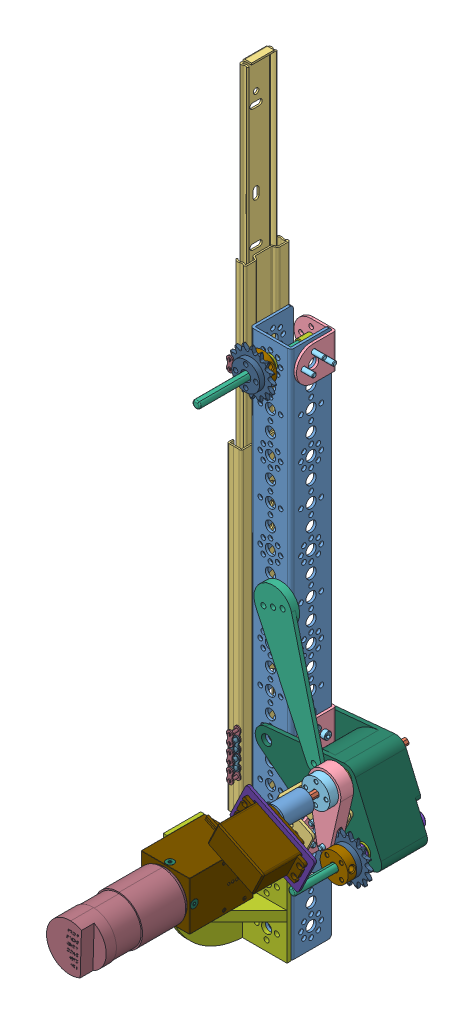
SolidWorks assembly 8699-18-204 Lander Latcher Drive, configuration Open. Lengths in mm.
Overall size (146.92 588.89 235.96).
103 component instances, 43 part files, 109 mates.
Components (placement in the parent):
- tetrix_739069-2: tetrix_739069 [Default] at (0 192 32) x (1 0 0) z (0 1 0) size (32 32 416)
- am-3643 NeveRest Sport, 104-1 with Motor-1: am-3643 NeveRest Sport, 104-1 with Motor [Default] at (37.7484 -95.467 21.4494) x (0 -1 0) z (0 0 1) size (48.85 48.85 145.31)
  - am-3643 NeveRest Sport, 104-1 with Motor(2)^am-3643 NeveRest Sport, 104-1 with Motor-1: am-3643 NeveRest Sport, 104-1 with Motor(2)^am-3643 NeveRest Sport, 104-1 with Motor [Default] at origin size (48.85 48.85 145.31) (virtual)
    - dv-XXXX Output Plug - 550 Sport^am-3643 NeveRest Sport, 104-1 with Motor(2)_am-3643 NeveRest Sport, 104-1 with Motor-1: dv-XXXX Output Plug - 550 Sport^am-3643 NeveRest Sport, 104-1 with Motor(2)_am-3643 NeveRest Sport, 104-1 with Motor [Default] at (30.7788 -45.9281 37.6212) x (-0.707107 -0.707107 0) z (0 0 1) size (34.54 34.54 34.87) (virtual)
      - dv-XXXX Output Plug with orbital bolt circle^dv-XXXX Output Plug - 550 Sport_am-3643 NeveRest Sport, 104-1 with Motor(2)_am-3643 NeveRest Sport, 104-1 with Motor-1: dv-XXXX Output Plug with orbital bolt circle^dv-XXXX Output Plug - 550 Sport_am-3643 NeveRest Sport, 104-1 with Motor(2)_am-3643 NeveRest Sport, 104-1 with Motor [Default] at (-7.0244 -4.5434 5.3964) size (34.54 34.54 17.78) (virtual)
      - BALL BEARING_5972K154^dv-XXXX Output Plug - 550 Sport_am-3643 NeveRest Sport, 104-1 with Motor(2)_am-3643 NeveRest Sport, 104-1 with Motor-1: BALL BEARING_5972K154^dv-XXXX Output Plug - 550 Sport_am-3643 NeveRest Sport, 104-1 with Motor(2)_am-3643 NeveRest Sport, 104-1 with Motor [Default] at (-7.0244 -4.5434 -0.8666) size (21 21 5) (virtual)
      - BALL BEARING_5972K154^dv-XXXX Output Plug - 550 Sport_am-3643 NeveRest Sport, 104-1 with Motor(2)_am-3643 NeveRest Sport, 104-1 with Motor-2: BALL BEARING_5972K154^dv-XXXX Output Plug - 550 Sport_am-3643 NeveRest Sport, 104-1 with Motor(2)_am-3643 NeveRest Sport, 104-1 with Motor [Default] at (-7.0244 -4.5434 10.1354) size (21 21 5) (virtual)
      - Nub Shaft^dv-XXXX Output Plug - 550 Sport_am-3643 NeveRest Sport, 104-1 with Motor(2)_am-3643 NeveRest Sport, 104-1 with Motor-1: Nub Shaft^dv-XXXX Output Plug - 550 Sport_am-3643 NeveRest Sport, 104-1 with Motor(2)_am-3643 NeveRest Sport, 104-1 with Motor [Default] at (-7.0244 -4.5434 20.2536) x (-0.939267 -0.343187 0) z (0.343187 -0.939267 0) size (19.05 34.87 19.05) (virtual)
    - dv-XXXX Carrier Stage 4-1 Planet, 5-1 Sun - 550 Sport^am-3643 NeveRest Sport, 104-1 with Motor(2)_am-3643 NeveRest Sport, 104-1 with Motor-1: dv-XXXX Carrier Stage 4-1 Planet, 5-1 Sun - 550 Sport^am-3643 NeveRest Sport, 104-1 with Motor(2)_am-3643 NeveRest Sport, 104-1 with Motor [Default] at (63.7059 -27.5277 100.4568) x (0.941837 -0.336071 0) z (-0.336071 -0.941837 0) size (29.23 15.47 28.59) (virtual)
      - am-2892+15T+pinion+3.2mm+bore^dv-XXXX Carrier Stage 4-1 Planet, 5-1 Sun - 550 Sport_am-3643 NeveRest Sport, 104-1 with Motor(2)_am-3643 NeveRest Sport, 104-1 with Motor-1: am-2892+15T+pinion+3.2mm+bore^dv-XXXX Carrier Stage 4-1 Planet, 5-1 Sun - 550 Sport_am-3643 NeveRest Sport, 104-1 with Motor(2)_am-3643 NeveRest Sport, 104-1 with Motor [Default] at (-25.9249 -17.3194 11.1026) x (0 -1 0) z (0.056322 0 -0.998413) size (5.31 10.12 10.18) (virtual)
      - am-2892+15T+pinion+3.2mm+bore^dv-XXXX Carrier Stage 4-1 Planet, 5-1 Sun - 550 Sport_am-3643 NeveRest Sport, 104-1 with Motor(2)_am-3643 NeveRest Sport, 104-1 with Motor-2: am-2892+15T+pinion+3.2mm+bore^dv-XXXX Carrier Stage 4-1 Planet, 5-1 Sun - 550 Sport_am-3643 NeveRest Sport, 104-1 with Motor(2)_am-3643 NeveRest Sport, 104-1 with Motor [Default] at (-16.9249 -17.3194 20.1026) x (0 -1 0) z (-0.169038 0 -0.98561) size (5.31 10.12 10.18) (virtual)
      - am-2892+15T+pinion+3.2mm+bore^dv-XXXX Carrier Stage 4-1 Planet, 5-1 Sun - 550 Sport_am-3643 NeveRest Sport, 104-1 with Motor(2)_am-3643 NeveRest Sport, 104-1 with Motor-3: am-2892+15T+pinion+3.2mm+bore^dv-XXXX Carrier Stage 4-1 Planet, 5-1 Sun - 550 Sport_am-3643 NeveRest Sport, 104-1 with Motor(2)_am-3643 NeveRest Sport, 104-1 with Motor [Default] at (-25.9249 -17.3194 29.1026) x (0 -1 0) z (-0.027474 0 -0.999623) size (5.31 10.12 10.18) (virtual)
      - am-2892+15T+pinion+3.2mm+bore^dv-XXXX Carrier Stage 4-1 Planet, 5-1 Sun - 550 Sport_am-3643 NeveRest Sport, 104-1 with Motor(2)_am-3643 NeveRest Sport, 104-1 with Motor-4: am-2892+15T+pinion+3.2mm+bore^dv-XXXX Carrier Stage 4-1 Planet, 5-1 Sun - 550 Sport_am-3643 NeveRest Sport, 104-1 with Motor(2)_am-3643 NeveRest Sport, 104-1 with Motor [Default] at (-34.9249 -17.3194 20.1026) x (0 -1 0) z (-0.064746 0 -0.997902) size (5.31 10.12 10.18) (virtual)
      - dv-XXXX - Carrier Plate 4-1 Planet, 5-1 Sun^dv-XXXX Carrier Stage 4-1 Planet, 5-1 Sun - 550 Sport_am-3643 NeveRest Sport, 104-1 with Motor(2)_am-3643 NeveRest Sport, 104-1 with Motor-1: dv-XXXX - Carrier Plate 4-1 Planet, 5-1 Sun^dv-XXXX Carrier Stage 4-1 Planet, 5-1 Sun - 550 Sport_am-3643 NeveRest Sport, 104-1 with Motor(2)_am-3643 NeveRest Sport, 104-1 with Motor [Default] at (-25.9249 -27.154 20.1026) size (25.04 10 25.04) (virtual)
      - 11T+pinion+3.2mm+bore^dv-XXXX Carrier Stage 4-1 Planet, 5-1 Sun - 550 Sport_am-3643 NeveRest Sport, 104-1 with Motor(2)_am-3643 NeveRest Sport, 104-1 with Motor-1: 11T+pinion+3.2mm+bore^dv-XXXX Carrier Stage 4-1 Planet, 5-1 Sun - 550 Sport_am-3643 NeveRest Sport, 104-1 with Motor(2)_am-3643 NeveRest Sport, 104-1 with Motor [Default] at (-25.9249 -22.6277 20.1026) x (0 -1 0) z (-0.988725 0 -0.149745) size (10 7.67 7.74) (virtual)
    - dv-XXXX Carrier Stage 5-1 Planet, 5-1 Sun^am-3643 NeveRest Sport, 104-1 with Motor(2)_am-3643 NeveRest Sport, 104-1 with Motor-1: dv-XXXX Carrier Stage 5-1 Planet, 5-1 Sun^am-3643 NeveRest Sport, 104-1 with Motor(2)_am-3643 NeveRest Sport, 104-1 with Motor [Default] at (6.8131 -34.6705 55.7021) x (-0.996841 0.079427 0) z (0.079427 0.996841 0) size (29.78 15.47 28.75) (virtual)
      - dv-XXXX - Carrier Plate 5-1 Planet, 5-1 Sun^dv-XXXX Carrier Stage 5-1 Planet, 5-1 Sun_am-3643 NeveRest Sport, 104-1 with Motor(2)_am-3643 NeveRest Sport, 104-1 with Motor-1: dv-XXXX - Carrier Plate 5-1 Planet, 5-1 Sun^dv-XXXX Carrier Stage 5-1 Planet, 5-1 Sun_am-3643 NeveRest Sport, 104-1 with Motor(2)_am-3643 NeveRest Sport, 104-1 with Motor [Default] at (-26.6144 7.6007 0.9439) size (25.04 10 25.04) (virtual)
      - 17T+pinion+3.2mm+bore^dv-XXXX Carrier Stage 5-1 Planet, 5-1 Sun_am-3643 NeveRest Sport, 104-1 with Motor(2)_am-3643 NeveRest Sport, 104-1 with Motor-1: 17T+pinion+3.2mm+bore^dv-XXXX Carrier Stage 5-1 Planet, 5-1 Sun_am-3643 NeveRest Sport, 104-1 with Motor(2)_am-3643 NeveRest Sport, 104-1 with Motor [Default] at (-35.0144 12.127 0.9439) x (0 1 0) z (-0.112997 0 0.993595) size (5.31 11.33 11.37) (virtual)
      - 17T+pinion+3.2mm+bore^dv-XXXX Carrier Stage 5-1 Planet, 5-1 Sun_am-3643 NeveRest Sport, 104-1 with Motor(2)_am-3643 NeveRest Sport, 104-1 with Motor-2: 17T+pinion+3.2mm+bore^dv-XXXX Carrier Stage 5-1 Planet, 5-1 Sun_am-3643 NeveRest Sport, 104-1 with Motor(2)_am-3643 NeveRest Sport, 104-1 with Motor [Default] at (-26.6144 12.127 9.3439) x (0 1 0) z (0.065842 0 0.99783) size (5.31 11.33 11.37) (virtual)
      - 17T+pinion+3.2mm+bore^dv-XXXX Carrier Stage 5-1 Planet, 5-1 Sun_am-3643 NeveRest Sport, 104-1 with Motor(2)_am-3643 NeveRest Sport, 104-1 with Motor-3: 17T+pinion+3.2mm+bore^dv-XXXX Carrier Stage 5-1 Planet, 5-1 Sun_am-3643 NeveRest Sport, 104-1 with Motor(2)_am-3643 NeveRest Sport, 104-1 with Motor [Default] at (-26.6144 12.127 -7.4561) x (0 1 0) z (0.038378 0 0.999263) size (5.31 11.33 11.37) (virtual)
      - 17T+pinion+3.2mm+bore^dv-XXXX Carrier Stage 5-1 Planet, 5-1 Sun_am-3643 NeveRest Sport, 104-1 with Motor(2)_am-3643 NeveRest Sport, 104-1 with Motor-4: 17T+pinion+3.2mm+bore^dv-XXXX Carrier Stage 5-1 Planet, 5-1 Sun_am-3643 NeveRest Sport, 104-1 with Motor(2)_am-3643 NeveRest Sport, 104-1 with Motor [Default] at (-18.2144 12.127 0.9439) x (0 1 0) z (0.205012 0 0.978759) size (5.31 11.33 11.37) (virtual)
      - 13T+pinion+3.2mm+bore^dv-XXXX Carrier Stage 5-1 Planet, 5-1 Sun_am-3643 NeveRest Sport, 104-1 with Motor(2)_am-3643 NeveRest Sport, 104-1 with Motor-1: 13T+pinion+3.2mm+bore^dv-XXXX Carrier Stage 5-1 Planet, 5-1 Sun_am-3643 NeveRest Sport, 104-1 with Motor(2)_am-3643 NeveRest Sport, 104-1 with Motor [Default] at (-26.6144 12.127 0.9439) x (0 -1 0) z (-0.984718 0 0.174154) size (10 8.9 8.96) (virtual)
    - dv-XXXX Carrier Stage 5-1 Planet, 0.3125 hex output^am-3643 NeveRest Sport, 104-1 with Motor(2)_am-3643 NeveRest Sport, 104-1 with Motor-1: dv-XXXX Carrier Stage 5-1 Planet, 0.3125 hex output^am-3643 NeveRest Sport, 104-1 with Motor(2)_am-3643 NeveRest Sport, 104-1 with Motor [Default] at (38.8348 -52.014 37.7173) x (0.574594 -0.818439 0) z (-0.818439 -0.574594 0) size (30.46 10 28.73) (virtual)
      - dv-XXXX - Carrier Plate 5-1 Planet, 0.3125 hex output^dv-XXXX Carrier Stage 5-1 Planet, 0.3125 hex output_am-3643 NeveRest Sport, 104-1 with Motor(2)_am-3643 NeveRest Sport, 104-1 with Motor-1: dv-XXXX - Carrier Plate 5-1 Planet, 0.3125 hex output^dv-XXXX Carrier Stage 5-1 Planet, 0.3125 hex output_am-3643 NeveRest Sport, 104-1 with Motor(2)_am-3643 NeveRest Sport, 104-1 with Motor [Default] at (-16.3468 15.5854 -4.8585) size (25.04 10 25.04) (virtual)
      - 17T+pinion+3.2mm+bore^dv-XXXX Carrier Stage 5-1 Planet, 0.3125 hex output_am-3643 NeveRest Sport, 104-1 with Motor(2)_am-3643 NeveRest Sport, 104-1 with Motor-1: 17T+pinion+3.2mm+bore^dv-XXXX Carrier Stage 5-1 Planet, 0.3125 hex output_am-3643 NeveRest Sport, 104-1 with Motor(2)_am-3643 NeveRest Sport, 104-1 with Motor [Default] at (-24.7468 20.1117 -4.8585) x (0 1 0) z (0.867721 0 0.497051) size (5.31 11.33 11.37) (virtual)
      - 17T+pinion+3.2mm+bore^dv-XXXX Carrier Stage 5-1 Planet, 0.3125 hex output_am-3643 NeveRest Sport, 104-1 with Motor(2)_am-3643 NeveRest Sport, 104-1 with Motor-2: 17T+pinion+3.2mm+bore^dv-XXXX Carrier Stage 5-1 Planet, 0.3125 hex output_am-3643 NeveRest Sport, 104-1 with Motor(2)_am-3643 NeveRest Sport, 104-1 with Motor [Default] at (-16.3468 20.1117 3.5415) x (0 1 0) z (-0.061129 0 0.99813) size (5.31 11.33 11.37) (virtual)
      - 17T+pinion+3.2mm+bore^dv-XXXX Carrier Stage 5-1 Planet, 0.3125 hex output_am-3643 NeveRest Sport, 104-1 with Motor(2)_am-3643 NeveRest Sport, 104-1 with Motor-3: 17T+pinion+3.2mm+bore^dv-XXXX Carrier Stage 5-1 Planet, 0.3125 hex output_am-3643 NeveRest Sport, 104-1 with Motor(2)_am-3643 NeveRest Sport, 104-1 with Motor [Default] at (-16.3468 20.1117 -13.2585) x (0 1 0) z (0.038378 0 0.999263) size (5.31 11.33 11.37) (virtual)
      - 17T+pinion+3.2mm+bore^dv-XXXX Carrier Stage 5-1 Planet, 0.3125 hex output_am-3643 NeveRest Sport, 104-1 with Motor(2)_am-3643 NeveRest Sport, 104-1 with Motor-4: 17T+pinion+3.2mm+bore^dv-XXXX Carrier Stage 5-1 Planet, 0.3125 hex output_am-3643 NeveRest Sport, 104-1 with Motor(2)_am-3643 NeveRest Sport, 104-1 with Motor [Default] at (-7.9468 20.1117 -4.8585) x (0 1 0) z (0.040503 0 0.999179) size (5.31 11.33 11.37) (virtual)
    - neveRest+15T+pinion^am-3643 NeveRest Sport, 104-1 with Motor(2)_am-3643 NeveRest Sport, 104-1 with Motor-1: neveRest+15T+pinion^am-3643 NeveRest Sport, 104-1 with Motor(2)_am-3643 NeveRest Sport, 104-1 with Motor [Default] at (-29.3619 -57.8483 143.121) x (-0.999543 0.030232 0) z (0 0 -1) size (38 38 89.79) (virtual)
      - am-3104 NeveRest Motor^neveRest+15T+pinion_am-3643 NeveRest Sport, 104-1 with Motor(2)_am-3643 NeveRest Sport, 104-1 with Motor-1: am-3104 NeveRest Motor^neveRest+15T+pinion_am-3643 NeveRest Sport, 104-1 with Motor(2)_am-3643 NeveRest Sport, 104-1 with Motor [Default] at (-61.259 21.9619 50.009) size (38 38 85.19) (virtual)
      - 15T+pinion+3.2mm+bore+motor^neveRest+15T+pinion_am-3643 NeveRest Sport, 104-1 with Motor(2)_am-3643 NeveRest Sport, 104-1 with Motor-1: 15T+pinion+3.2mm+bore+motor^neveRest+15T+pinion_am-3643 NeveRest Sport, 104-1 with Motor(2)_am-3643 NeveRest Sport, 104-1 with Motor [Default] at (-61.259 21.9619 54.7947) x (0 0 1) z (-0.930076 -0.367368 0) size (9.81 10.12 10.18) (virtual)
    - 91294A126_BLACK ALLOY STEEL FLAT-HEAD SOCKET CAP SCREW_91294A126^am-3643 NeveRest Sport, 104-1 with Motor(2)_am-3643 NeveRest Sport, 104-1 with Motor-1: 91294A126_BLACK ALLOY STEEL FLAT-HEAD SOCKET CAP SCREW_91294A126^am-3643 NeveRest Sport, 104-1 with Motor(2)_am-3643 NeveRest Sport, 104-1 with Motor [Default] at (13.433 -37.7484 46.9556) x (0 0 1) z (-1 0 0) size (6 6 6.01) (virtual)
    - Thrust Washer^am-3643 NeveRest Sport, 104-1 with Motor(2)_am-3643 NeveRest Sport, 104-1 with Motor-1: Thrust Washer^am-3643 NeveRest Sport, 104-1 with Motor(2)_am-3643 NeveRest Sport, 104-1 with Motor [Default] at (32.533 -37.7484 84.9184) x (0.422278 0.906466 0) z (0 0 -1) size (28.45 28.45 0.51) (virtual)
    - dv-XXXX Motor Mount Plug^am-3643 NeveRest Sport, 104-1 with Motor(2)_am-3643 NeveRest Sport, 104-1 with Motor-1: dv-XXXX Motor Mount Plug^am-3643 NeveRest Sport, 104-1 with Motor(2)_am-3643 NeveRest Sport, 104-1 with Motor [Default] at (32.533 -37.7484 93.1201) x (-0.707107 0.707107 0) z (0 0 -1) size (30.99 30.99 8.13) (virtual)
    - 91294A126_BLACK ALLOY STEEL FLAT-HEAD SOCKET CAP SCREW_91294A126^am-3643 NeveRest Sport, 104-1 with Motor(2)_am-3643 NeveRest Sport, 104-1 with Motor-2: 91294A126_BLACK ALLOY STEEL FLAT-HEAD SOCKET CAP SCREW_91294A126^am-3643 NeveRest Sport, 104-1 with Motor(2)_am-3643 NeveRest Sport, 104-1 with Motor [Default] at (32.533 -18.6484 89.5006) x (0.466078 0 0.884744) z (0 1 0) size (6 6 6.01) (virtual)
    - 91294A126_BLACK ALLOY STEEL FLAT-HEAD SOCKET CAP SCREW_91294A126^am-3643 NeveRest Sport, 104-1 with Motor(2)_am-3643 NeveRest Sport, 104-1 with Motor-3: 91294A126_BLACK ALLOY STEEL FLAT-HEAD SOCKET CAP SCREW_91294A126^am-3643 NeveRest Sport, 104-1 with Motor(2)_am-3643 NeveRest Sport, 104-1 with Motor [Default] at (32.533 -18.6484 46.9556) x (0.982767 0 0.184847) z (0 1 0) size (6 6 6.01) (virtual)
    - 91294A126_BLACK ALLOY STEEL FLAT-HEAD SOCKET CAP SCREW_91294A126^am-3643 NeveRest Sport, 104-1 with Motor(2)_am-3643 NeveRest Sport, 104-1 with Motor-4: 91294A126_BLACK ALLOY STEEL FLAT-HEAD SOCKET CAP SCREW_91294A126^am-3643 NeveRest Sport, 104-1 with Motor(2)_am-3643 NeveRest Sport, 104-1 with Motor [Default] at (13.433 -37.7484 89.5006) x (0 0 1) z (-1 0 0) size (6 6 6.01) (virtual)
    - 91294A126_BLACK ALLOY STEEL FLAT-HEAD SOCKET CAP SCREW_91294A126^am-3643 NeveRest Sport, 104-1 with Motor(2)_am-3643 NeveRest Sport, 104-1 with Motor-5: 91294A126_BLACK ALLOY STEEL FLAT-HEAD SOCKET CAP SCREW_91294A126^am-3643 NeveRest Sport, 104-1 with Motor(2)_am-3643 NeveRest Sport, 104-1 with Motor [Default] at (51.633 -37.7484 46.9556) x (0 -0.421523 0.906818) z (1 0 0) size (6 6 6.01) (virtual)
    - 91294A126_BLACK ALLOY STEEL FLAT-HEAD SOCKET CAP SCREW_91294A126^am-3643 NeveRest Sport, 104-1 with Motor(2)_am-3643 NeveRest Sport, 104-1 with Motor-6: 91294A126_BLACK ALLOY STEEL FLAT-HEAD SOCKET CAP SCREW_91294A126^am-3643 NeveRest Sport, 104-1 with Motor(2)_am-3643 NeveRest Sport, 104-1 with Motor [Default] at (51.633 -37.7484 89.5006) x (0 -0.712248 -0.701928) z (1 0 0) size (6 6 6.01) (virtual)
    - dv-XXXX - 3 Stage 550 Sport Ring Gear Housing^am-3643 NeveRest Sport, 104-1 with Motor(2)_am-3643 NeveRest Sport, 104-1 with Motor-1: dv-XXXX - 3 Stage 550 Sport Ring Gear Housing^am-3643 NeveRest Sport, 104-1 with Motor(2)_am-3643 NeveRest Sport, 104-1 with Motor [Default] at (13.483 -56.7984 68.2281) size (38.1 38.1 49.91) (virtual)
    - 10-32 x 0.25 Set Screw Cup Point^am-3643 NeveRest Sport, 104-1 with Motor(2)_am-3643 NeveRest Sport, 104-1 with Motor-1: 10-32 x 0.25 Set Screw Cup Point^am-3643 NeveRest Sport, 104-1 with Motor(2)_am-3643 NeveRest Sport, 104-1 with Motor [Default] at (42.0774 -42.1846 29.5006) x (-0.906832 0.421492 0) z (0.0498 0.107144 0.992995) size (6.35 4.83 4.83) (virtual)
    - M3x0.5x6mm SHCS_91290A111^am-3643 NeveRest Sport, 104-1 with Motor(2)_am-3643 NeveRest Sport, 104-1 with Motor-1: M3x0.5x6mm SHCS_91290A111^am-3643 NeveRest Sport, 104-1 with Motor(2)_am-3643 NeveRest Sport, 104-1 with Motor [Default] at (23.6942 -46.5873 96.1483) size (5.5 5.5 9.01) (virtual)
    - M3x0.5x6mm SHCS_91290A111^am-3643 NeveRest Sport, 104-1 with Motor(2)_am-3643 NeveRest Sport, 104-1 with Motor-2: M3x0.5x6mm SHCS_91290A111^am-3643 NeveRest Sport, 104-1 with Motor(2)_am-3643 NeveRest Sport, 104-1 with Motor [Default] at (41.3718 -28.9096 96.1483) size (5.5 5.5 9.01) (virtual)
- 11435A110_SIDE-MOUNT DRAWER SLIDE-1: 11435A110_SIDE-MOUNT DRAWER SLIDE [Open] at (-21.6388 1.918 16) x (0 -1 0) z (-1 0 0) size (503.94 45.64 12.7)
- Pitsco Education-739062-1: Pitsco Education-739062 [Default] at (-3.4747 191.2436 18.0384) x (0 -1 0) z (0 0 -1) size (27 31.5 31.5)
- tetrix_739097-1: tetrix_739097 [Default] at (14 192 8) x (0 1 0) z (0 0 1) size (5.74 16.21 5.74)
- tetrix_739097-2: tetrix_739097 [Default] at (14 200 16) x (0 1 0) z (0 0 1) size (5.74 16.21 5.74)
- tetrix_739097-3: tetrix_739097 [Default] at (14 192 24) x (0 1 0) z (0 0 1) size (5.74 16.21 5.74)
- tetrix_744708_6mm-1: tetrix_744708_6mm [Default] at (-41.9477 150.1357 -24.7204) size (6 5.5 100)
- tetrix_739091-7: tetrix_739091 [Default] at (0 192 -3.4) x (1 0 0) z (0 -1 0) size (11 12.4 11)
- tetrix_739091-8: tetrix_739091 [Default] at (0 192 33.4) x (0.999564 -0.029538 0) z (0.029538 0.999564 0) size (11 12.4 11)
- tetrix_739092_collar-2: tetrix_739092_collar [Default] at (0 192 -6.5) size (11 11 6.2)
- tetrix_739079_collar-2: tetrix_739079_collar [Default] at (0 192 44.65) size (22 22 9.5)
- tetrix_739165-3: tetrix_739165 [Default] at (0 192 47.45) size (36 36 6.8)
- tetrix_741665_6mm ID Plastic Bushing_Spacer-1: tetrix_741665_6mm ID Plastic Bushing_Spacer [Default] at (0 192 36.4) x (0.793594 -0.608447 0) z (0 0 1) size (9.4 9.4 3)
- tetrix_741665_6mm ID Plastic Bushing_Spacer-2: tetrix_741665_6mm ID Plastic Bushing_Spacer [Default] at (0 192 34.9) x (-0.923728 -0.383049 0) z (0 0 -1) size (9.4 9.4 3)
- tetrix_744708_6mm-2: tetrix_744708_6mm [Default] at (-41.9477 -169.8643 -61.3204) size (6 5.5 100)
- Pitsco Education-739062-2: Pitsco Education-739062 [Default] at (-3.4747 -128.7564 18.0384) x (0 -1 0) z (0 0 -1) size (27 31.5 31.5)
- tetrix_739091-9: tetrix_739091 [Default] at (0 -128 -3.4) x (-0.332615 -0.943063 0) z (-0.943063 0.332615 0) size (11 12.4 11)
- tetrix_739091-10: tetrix_739091 [Default] at (0 -128 33.4) x (0.998296 -0.058356 0) z (0.058356 0.998296 0) size (11 12.4 11)
- tetrix_739092_collar-3: tetrix_739092_collar [Default] at (0 -128 -6.5) size (11 11 6.2)
- tetrix_739165-4: tetrix_739165 [Default] at (0 -128 44.65) x (-0.343187 0.939267 0) z (0 0 -1) size (36 36 6.8)
- tetrix_739097-4: tetrix_739097 [Default] at (14 -128 24) x (0 1 0) z (0 0 1) size (5.74 16.21 5.74)
- tetrix_739097-5: tetrix_739097 [Default] at (14 -120 16) x (0 1 0) z (0 0 1) size (5.74 16.21 5.74)
- tetrix_739097-6: tetrix_739097 [Default] at (14 -128 8) x (0 1 0) z (0 0 1) size (5.74 16.21 5.74)
- tetrix_739111_BHCS 6-32 x 0.375-1: tetrix_739111_BHCS 6-32 x 0.375 [92949A146] at (-7.5141 -130.7455 38.7958) x (-0.923728 -0.383049 0) z (0 0 -1) size (6.65 6.65 11.49)
- tetrix_739111_BHCS 6-32 x 0.375-2: tetrix_739111_BHCS 6-32 x 0.375 [92949A146] at (7.5141 -125.2545 38.7958) x (-0.923728 -0.383049 0) z (0 0 -1) size (6.65 6.65 11.49)
- tetrix_739097-7: tetrix_739097 [Default] at (-2.7455 -120.4859 40.65) x (0.975434 -0.220292 0) z (0.220292 0.975434 0) size (5.74 16.21 5.74)
- tetrix_39173_outside_link-1: tetrix_39173_outside_link [Default] at (-14.7363 191.7562 46.05) x (0 1 0) z (0 0 1) size (11.43 5.08 7.82)
- tetrix_39173_outside_link-2: tetrix_39173_outside_link [Default] at (-14.7363 -63.2855 46.05) x (0 -1 0) z (0 0 1) size (11.43 5.08 7.82)
- tetrix_39173_outside_link-3: tetrix_39173_outside_link [Default] at (-14.7363 -75.9855 46.05) x (0 -1 0) z (0 0 1) size (11.43 5.08 7.82)
- tetrix_39173_outside_link-4: tetrix_39173_outside_link [Default] at (-14.7363 -88.6855 46.05) x (0 -1 0) z (0 0 1) size (11.43 5.08 7.82)
- tetrix_39173_inside_link-1: tetrix_39173_inside_link [Default] at (-14.7363 -69.6355 46.05) x (0 -1 0) z (0 0 1) size (11.43 5.08 4.9)
- tetrix_39173_inside_link-2: tetrix_39173_inside_link [Default] at (-14.7363 -82.3355 46.05) x (0 -1 0) z (0 0 1) size (11.43 5.08 4.9)
- 8699-18-205 Lander Latcher Drive Adj-1: 8699-18-205 Lander Latcher Drive Adj [Default] at (0 -64 15) x (0.899951 -0.435991 0) z (0 0 1) size (116.51 74.65 143.2)
  - 8699-18-364 Lock Adjustment Plate-1: 8699-18-364 Lock Adjustment Plate [Default] at origin size (108.78 66.42 40)
  - tetrix_739107_32mm_standoff-1: tetrix_739107_32mm_standoff [Default] at (80.8213 0.0145 47.7605) size (7.16 6.2 32)
  - tetrix_741789-1: tetrix_741789 [Default] at (52.7846 32 86) x (1 0 0) z (0 0 -1) size (59.8 60.75 2)
  - tetrix_739197_servo-1: tetrix_739197_servo [Default] at (52.7846 32 88.5) x (0 1 0) z (-1 0 0) size (20 43.2 56.6)
  - tetrix_739278_axle_adapter-1: tetrix_739278_axle_adapter [Default] at (52.7846 32 75.2) x (0.998477 0.055163 0) z (0 0 -1) size (16 16 23)
  - tetrix_739088-1: tetrix_739088 [Default] at (52.7846 32 21.9) x (-0.87123 0.490874 0) z (0 0 -1) size (4.73 4.46 100)
  - tetrix_744708_6mm-2: tetrix_744708_6mm [Default] at (92.5192 -58.7572 -38.7204) x (0.607985 0.793949 0) z (0 0 1) size (6 5.5 100)
  - tetrix_739091-1: tetrix_739091 [Default] at (52.7846 32 -21.4) x (1 0 0) z (0 -1 0) size (11 12.4 11)
  - tetrix_739091-2: tetrix_739091 [Default] at (84.7846 0 21.4) x (-0.82449 0.565877 0) z (-0.565877 -0.82449 0) size (11 12.4 11)
  - tetrix_739091-3: tetrix_739091 [Default] at (84.7846 0 -17.4) x (-0.539749 -0.841826 0) z (-0.841826 0.539749 0) size (11 12.4 11)
  - tetrix_739079_collar-1: tetrix_739079_collar [Default] at (84.7846 0 36.45) x (0.312774 0.949828 0) z (0 0 -1) size (22 22 9.5)
  - tetrix_739165-1: tetrix_739165 [Default] at (84.7846 0 32.45) x (-0.312774 -0.949828 0) z (0 0 1) size (36 36 6.8)
  - tetrix_739065-2: tetrix_739065 [Default] at (36.7846 0 36) x (0 0 1) z (0 1 0) size (32 32 32)
  - tetrix_739091-4: tetrix_739091 [Default] at (52.7846 32 21.4) x (-0.923728 -0.383049 0) z (0.383049 -0.923728 0) size (11 12.4 11)
  - tetrix_739097-1: tetrix_739097 [Default] at (44.7846 0 17) x (0.933008 0.359855 0) z (-0.359855 0.933008 0) size (5.74 16.21 5.74)
  - tetrix_739097-2: tetrix_739097 [Default] at (52.7846 -8 17) x (0.058002 0.998316 0) z (-0.998316 0.058002 0) size (5.74 16.21 5.74)
  - 8699-18-366 Lock-1: 8699-18-366 Lock [Default] at (52.7846 32 31.05) x (0.909547 0.415601 0) z (0 0 1) size (26 57.92 10)
  - tetrix_739097-3: tetrix_739097 [Default] at (69.3764 -4.3113 26.05) x (-0.975108 0.22173 0) z (-0.22173 -0.975108 0) size (5.74 16.21 5.74)
  - tetrix_739172_collar-1: tetrix_739172_collar [Default] at (52.7846 32 36.05) x (-0.909547 -0.415601 0) z (0 0 -1) size (22.1 22.1 9.5)
  - tetrix_739092_collar-1: tetrix_739092_collar [Default] at (84.7846 0 -20.5) x (0.871034 0.491223 0) z (0 0 1) size (11 11 6.2)
  - tetrix_739092_collar-2: tetrix_739092_collar [Default] at (84.7846 0 24.5) x (0.871034 0.491223 0) z (0 0 1) size (11 11 6.2)
- Pitsco Education-739062-3: Pitsco Education-739062 [Default] at (-3.4747 -64.7564 18.0384) x (0 -1 0) z (0 0 -1) size (27 31.5 31.5)
- tetrix_739097-8: tetrix_739097 [Default] at (18 -56 16) x (0 0.381849 -0.924225) z (0 -0.924225 -0.381849) size (5.74 16.21 5.74)
- tetrix_739097-9: tetrix_739097 [Default] at (18 -64 8) x (0 -1 0) z (0 0 1) size (5.74 16.21 5.74)
- tetrix_739097-10: tetrix_739097 [Default] at (18 -64 24) x (0 -1 0) z (0 0 1) size (5.74 16.21 5.74)
- tetrix_739097-13: tetrix_739097 [Default] at (18 -72 16) x (0 1 0) z (0 0 -1) size (5.74 16.21 5.74)
- 8699-18-365 Lock Adjustment Reinforcement-1: 8699-18-365 Lock Adjustment Reinforcement [Default] at (40.062 -58.4877 35) x (0.333979 -0.94258 0) z (-0.94258 -0.333979 0) size (117 6 30)
- 8699-18-369 LL Motor Mount 1-1: 8699-18-369 LL Motor Mount 1 [Default] at (-19.05 -160 16) x (0 0 1) z (0 -1 0) size (94.18 38.05 99.05)
Mates (geometry in assembly coordinates):
- Coincident57: coincident: plane of tetrix_739069-2 through (16 208 0) normal (0 0 -1); plane of assembly through (0 0 0) normal (0 0 1)
- Symmetric1: symmetric: plane of tetrix_739069-2 through (16 208 32) normal (0 1 0); plane of tetrix_739069-2 through (16 -208 0) normal (0 -1 0); plane of assembly
- Symmetric2: symmetric: plane of tetrix_739069-2 through (16 192 32) normal (1 0 0); plane of tetrix_739069-2 through (-16 192 32) normal (-1 0 0); plane of assembly
- Concentric99: concentric: cylinder of tetrix_739069-2 through (16 192 16) axis (1 0 0) radius 4; cylinder of ? through (-14 192 16) axis (1 0 0) radius 4
- Coincident60: coincident: plane of tetrix_739069-2 through (16 192 32) normal (1 0 0); plane of ? through (16 175.569 31.557) normal (-1 0 0)
- Concentric100: concentric: cylinder of tetrix_739069-2 through (16 192 16) axis (1 0 0) radius 4; cylinder of Pitsco Education-739062-1 through (-13.5 192 16) axis (1 0 0) radius 4
- Coincident61: coincident: plane of tetrix_739069-2 through (16 192 32) normal (1 0 0); plane of Pitsco Education-739062-1 through (16 205.5 29.5) normal (-1 0 0)
- Concentric101: concentric: cylinder of tetrix_739069-2 through (0 192 32) axis (0 0 1) radius 4; cylinder of Pitsco Education-739062-1 through (0 192 29.5) axis (0 0 -1) radius 4
- Concentric102: concentric: cylinder of tetrix_739069-2 through (16 200 16) axis (1 0 0) radius 1.85; cylinder of tetrix_739097-2 through (26.7 200 16) axis (-1 0 0) radius 1.7526
- Coincident62: coincident: plane of tetrix_739069-2 through (14 -208 30) normal (-1 0 0); plane of tetrix_739097-2 through (14 200 16) normal (1 0 0)
- Concentric103: concentric: cylinder of tetrix_739069-2 through (16 192 24) axis (1 0 0) radius 1.85; cylinder of tetrix_739097-3 through (26.7 192 24) axis (-1 0 0) radius 1.7526
- Coincident63: coincident: plane of tetrix_739069-2 through (14 -208 30) normal (-1 0 0); plane of tetrix_739097-3 through (14 192 24) normal (1 0 0)
- Concentric104: concentric: cylinder of tetrix_739069-2 through (16 192 8) axis (1 0 0) radius 1.85; cylinder of tetrix_739097-1 through (26.7 192 8) axis (-1 0 0) radius 1.7526
- Coincident64: coincident: plane of tetrix_739069-2 through (14 -208 30) normal (-1 0 0); plane of tetrix_739097-1 through (14 192 8) normal (1 0 0)
- Concentric105: concentric: cylinder of Pitsco Education-739062-1 through (0 192 29.5) axis (0 0 -1) radius 4; cylinder of tetrix_744708_6mm-1 through (0 192 -9.6) axis (0 0 1) radius 3
- Concentric106: concentric: cylinder of Pitsco Education-739062-1 through (0 192 29.5) axis (0 0 -1) radius 4; cylinder of tetrix_739091-7 through (0 192 -3.4) axis (0 0 1) radius 3.925
- Coincident65: coincident: plane of Pitsco Education-739062-1 through (-13.5 205.5 -2) normal (0 0 -1); plane of tetrix_739091-7 through (3.925 192 -2) normal (0 0 1)
- Concentric107: concentric: cylinder of tetrix_739069-2 through (0 192 32) axis (0 0 1) radius 4; cylinder of tetrix_739091-8 through (0 192 33.4) axis (0 0 -1) radius 3.925
- Coincident66: coincident: plane of tetrix_739069-2 through (16 -208 32) normal (0 0 1); plane of tetrix_739091-8 through (3.9233 191.8841 32) normal (0 0 -1)
- Concentric108: concentric: cylinder of tetrix_744708_6mm-1 through (0 192 -9.6) axis (0 0 1) radius 3; cylinder of tetrix_739092_collar-2 through (0 192 -3.4) axis (0 0 1) radius 2.425
- Coincident67: coincident: plane of tetrix_739091-7 through (5.5 192 -3.4) normal (0 0 -1); plane of tetrix_739092_collar-2 through (0 192 -3.4) normal (0 0 1)
- Coincident68: coincident: line of tetrix_744708_6mm-1 through (-1.3229 193.5 -9.6) axis (1 0 0); plane of tetrix_739092_collar-2 through (5.5 192 -9.6) normal (0 0 -1)
- Concentric109: concentric: cylinder of tetrix_744708_6mm-1 through (0 192 -9.6) axis (0 0 1) radius 3; cylinder of tetrix_739079_collar-2 through (0 192 47.4) axis (0 0 -1) radius 3.05
- Coincident69: coincident: plane of tetrix_739091-8 through (5.4976 191.8375 33.4) normal (0 0 1); plane of tetrix_739079_collar-2 through (0 192 33.4) normal (0 0 -1)
- Coincident70: coincident: plane of tetrix_739079_collar-2 through (0 192 44.65) normal (0 0 1); plane of tetrix_739165-3 through (0 192 44.65) normal (0 0 -1)
- Concentric110: concentric: cylinder of tetrix_744708_6mm-1 through (0 192 -9.6) axis (0 0 1) radius 3; cylinder of tetrix_739165-3 through (0 192 51.45) axis (0 0 1) radius 4
- Concentric111: concentric: cylinder of tetrix_739079_collar-2 through (0 200 37.9) axis (0 0 -1) radius 1.3525; cylinder of tetrix_739165-3 through (0 200 51.45) axis (0 0 1) radius 1.8
- Concentric112: concentric: cylinder of tetrix_739069-2 through (16 -128 16) axis (1 0 0) radius 4; cylinder of Pitsco Education-739062-2 through (-13.5 -128 16) axis (1 0 0) radius 4
- Coincident71: coincident: plane of tetrix_739069-2 through (16 192 32) normal (1 0 0); plane of Pitsco Education-739062-2 through (16 -114.5 29.5) normal (-1 0 0)
- Concentric113: concentric: cylinder of tetrix_739069-2 through (0 -128 32) axis (0 0 1) radius 4; cylinder of Pitsco Education-739062-2 through (0 -128 29.5) axis (0 0 -1) radius 4
- Concentric114: concentric: cylinder of tetrix_744708_6mm-2 through (0 -128 -46.2) axis (0 0 1) radius 3; cylinder of Pitsco Education-739062-2 through (0 -128 29.5) axis (0 0 -1) radius 4
- Concentric115: concentric: cylinder of Pitsco Education-739062-2 through (0 -128 29.5) axis (0 0 -1) radius 4; cylinder of tetrix_739091-9 through (0 -128 -3.4) axis (0 0 1) radius 3.925
- Coincident72: coincident: plane of Pitsco Education-739062-2 through (-13.5 -114.5 -2) normal (0 0 -1); plane of tetrix_739091-9 through (-1.3055 -131.7015 -2) normal (0 0 1)
- Concentric116: concentric: cylinder of tetrix_744708_6mm-2 through (0 -128 -46.2) axis (0 0 1) radius 3; cylinder of tetrix_739092_collar-3 through (0 -128 -3.4) axis (0 0 1) radius 2.425
- Coincident73: coincident: plane of tetrix_739091-9 through (-1.8294 -133.1868 -3.4) normal (0 0 -1); plane of tetrix_739092_collar-3 through (0 -128 -3.4) normal (0 0 1)
- Concentric117: concentric: cylinder of tetrix_744708_6mm-2 through (0 -128 -46.2) axis (0 0 1) radius 3; cylinder of tetrix_739091-10 through (0 -128 33.4) axis (0 0 -1) radius 3.925
- Coincident74: coincident: plane of tetrix_739069-2 through (16 -208 32) normal (0 0 1); plane of tetrix_739091-10 through (3.9183 -128.229 32) normal (0 0 -1)
- Concentric118: concentric: cylinder of tetrix_744708_6mm-2 through (0 -128 -26.5587) axis (0 0 1) radius 3; cylinder of ? through (0 -128 42.9) axis (0 0 -1) radius 3.05
- Coincident75: coincident: plane of tetrix_739091-10 through (5.4906 -128.321 33.4) normal (0 0 1); plane of ? through (0 -128 33.4) normal (0 0 -1)
- Concentric119: concentric: cylinder of tetrix_744708_6mm-2 through (0 -128 -46.2) axis (0 0 1) radius 3; cylinder of tetrix_739165-4 through (0 -128 40.65) axis (0 0 -1) radius 4
- Concentric120: concentric: cylinder of ? through (-0.8363 -120.0438 33.4) axis (0 0 -1) radius 1.3525; cylinder of tetrix_739165-4 through (-0.8363 -120.0438 46.95) axis (0 0 1) radius 1.8
- Coincident76: coincident: plane of ? through (0 -128 40.15) normal (0 0 1); plane of tetrix_739165-4 through (0 -128 40.15) normal (0 0 -1)
- Concentric121: concentric: cylinder of tetrix_739069-2 through (16 -128 24) axis (1 0 0) radius 1.85; cylinder of tetrix_739097-4 through (26.7 -128 24) axis (-1 0 0) radius 1.7526
- Coincident77: coincident: plane of tetrix_739069-2 through (14 -208 30) normal (-1 0 0); plane of tetrix_739097-4 through (14 -128 24) normal (1 0 0)
- Concentric122: concentric: cylinder of tetrix_739069-2 through (16 -120 16) axis (1 0 0) radius 1.85; cylinder of tetrix_739097-5 through (26.7 -120 16) axis (-1 0 0) radius 1.7526
- Coincident78: coincident: plane of tetrix_739069-2 through (14 -208 30) normal (-1 0 0); plane of tetrix_739097-5 through (14 -120 16) normal (1 0 0)
- Concentric123: concentric: cylinder of tetrix_739097-6 through (26.7 -128 8) axis (-1 0 0) radius 1.7526; cylinder of tetrix_739069-2 through (16 -128 8) axis (1 0 0) radius 1.85
- Coincident79: coincident: plane of tetrix_739069-2 through (14 -208 30) normal (-1 0 0); plane of tetrix_739097-6 through (14 -128 8) normal (1 0 0)
- Coincident80: coincident: plane of tetrix_744708_6mm-2 through (0 -128 53.8) normal (0 0 1); plane of am-3643 NeveRest Sport, 104-1 with Motor-1/am-3643 NeveRest Sport, 104-1 with Motor(2)^am-3643 NeveRest Sport, 104-1 with Motor-1/dv-XXXX Output Plug - 550 Sport^am-3643 NeveRest Sport, 104-1 with Motor(2)_am-3643 NeveRest Sport, 104-1 with Motor-1/Nub Shaft^dv-XXXX Output Plug - 550 Sport_am-3643 NeveRest Sport, 104-1 with Motor(2)_am-3643 NeveRest Sport, 104-1 with Motor-1 through (0 -128 53.8) normal (0 0 -1)
- Concentric124: concentric: cylinder of tetrix_744708_6mm-2 through (0 -128 -46.2) axis (0 0 1) radius 3; cylinder of am-3643 NeveRest Sport, 104-1 with Motor-1/am-3643 NeveRest Sport, 104-1 with Motor(2)^am-3643 NeveRest Sport, 104-1 with Motor-1/dv-XXXX Output Plug - 550 Sport^am-3643 NeveRest Sport, 104-1 with Motor(2)_am-3643 NeveRest Sport, 104-1 with Motor-1/Nub Shaft^dv-XXXX Output Plug - 550 Sport_am-3643 NeveRest Sport, 104-1 with Motor(2)_am-3643 NeveRest Sport, 104-1 with Motor-1 through (0 -128 44.45) axis (0 0 1) radius 3.05
- Concentric125: concentric: cylinder of tetrix_739165-4 through (7.5141 -125.2545 40.65) axis (0 0 -1) radius 1.8; cylinder of am-3643 NeveRest Sport, 104-1 with Motor-1/am-3643 NeveRest Sport, 104-1 with Motor(2)^am-3643 NeveRest Sport, 104-1 with Motor-1/dv-XXXX Output Plug - 550 Sport^am-3643 NeveRest Sport, 104-1 with Motor(2)_am-3643 NeveRest Sport, 104-1 with Motor-1/Nub Shaft^dv-XXXX Output Plug - 550 Sport_am-3643 NeveRest Sport, 104-1 with Motor(2)_am-3643 NeveRest Sport, 104-1 with Motor-1 through (7.5141 -125.2545 47.45) axis (0 0 -1) radius 1.3526
- Coincident81: coincident: plane of tetrix_739165-4 through (0 -128 47.45) normal (0 0 1); plane of am-3643 NeveRest Sport, 104-1 with Motor-1/am-3643 NeveRest Sport, 104-1 with Motor(2)^am-3643 NeveRest Sport, 104-1 with Motor-1/dv-XXXX Output Plug - 550 Sport^am-3643 NeveRest Sport, 104-1 with Motor(2)_am-3643 NeveRest Sport, 104-1 with Motor-1/Nub Shaft^dv-XXXX Output Plug - 550 Sport_am-3643 NeveRest Sport, 104-1 with Motor(2)_am-3643 NeveRest Sport, 104-1 with Motor-1 through (0 -128 47.45) normal (0 0 -1)
- Coincident82: coincident: plane of tetrix_739165-3 through (0 192 47.45) normal (0 0 1); plane of tetrix_739165-4 through (0 -128 47.45) normal (0 0 1)
- Parallel7: parallel: plane of am-3643 NeveRest Sport, 104-1 with Motor-1/am-3643 NeveRest Sport, 104-1 with Motor(2)^am-3643 NeveRest Sport, 104-1 with Motor-1/dv-XXXX - 3 Stage 550 Sport Ring Gear Housing^am-3643 NeveRest Sport, 104-1 with Motor(2)_am-3643 NeveRest Sport, 104-1 with Motor-1 through (19.05 -108.95 114.633) normal (1 0 0); plane of tetrix_739069-2 through (16 192 32) normal (1 0 0)
- Concentric126: concentric: cylinder of tetrix_739165-4 through (-7.5141 -130.7455 40.65) axis (0 0 -1) radius 1.8; cylinder of tetrix_739111_BHCS 6-32 x 0.375-1 through (-7.5141 -130.7455 50.175) axis (0 0 1) radius 1.7526
- Coincident84: coincident: plane of tetrix_739165-4 through (0 -128 40.65) normal (0 0 -1); plane of tetrix_739111_BHCS 6-32 x 0.375-1 through (-6.2396 -133.8191 40.65) normal (0 0 1)
- Concentric127: concentric: cylinder of tetrix_739165-4 through (7.5141 -125.2545 40.65) axis (0 0 -1) radius 1.8; cylinder of tetrix_739111_BHCS 6-32 x 0.375-2 through (7.5141 -125.2545 50.175) axis (0 0 1) radius 1.7526
- Coincident85: coincident: plane of tetrix_739165-4 through (0 -128 40.65) normal (0 0 -1); plane of tetrix_739111_BHCS 6-32 x 0.375-2 through (8.7887 -128.3281 40.65) normal (0 0 1)
- Concentric128: concentric: cylinder of tetrix_739165-4 through (-2.7455 -120.4859 47.45) axis (0 0 1) radius 1.8; cylinder of tetrix_739097-7 through (-2.7455 -120.4859 53.35) axis (0 0 -1) radius 1.7526
- Coincident86: coincident: plane of tetrix_739165-4 through (0 -128 40.65) normal (0 0 -1); plane of tetrix_739097-7 through (-2.7455 -120.4859 40.65) normal (0 0 1)
- Concentric129: concentric: cylinder of tetrix_744708_6mm-1 through (0 192 -9.6) axis (0 0 1) radius 3; cylinder of tetrix_741665_6mm ID Plastic Bushing_Spacer-2 through (0 192 36.4) axis (0 0 -1) radius 3.015
- Concentric130: concentric: cylinder of tetrix_744708_6mm-1 through (0 192 -9.6) axis (0 0 1) radius 3; cylinder of tetrix_741665_6mm ID Plastic Bushing_Spacer-1 through (0 192 34.9) axis (0 0 1) radius 3.015
- Coincident87: coincident: plane of tetrix_741665_6mm ID Plastic Bushing_Spacer-1 through (0 192 36.4) normal (0 0 -1); plane of tetrix_741665_6mm ID Plastic Bushing_Spacer-2 through (0 192 36.4) normal (0 0 1)
- Coincident88: coincident: plane of tetrix_741665_6mm ID Plastic Bushing_Spacer-1 through (0 192 41.6694) normal (0.608447 0.793594 0); plane of tetrix_741665_6mm ID Plastic Bushing_Spacer-2 through (0 192 29.5834) normal (-0.608447 -0.793594 0)
- Coincident89: coincident: plane of tetrix_739091-8 through (5.4976 191.8375 33.4) normal (0 0 1); plane of tetrix_741665_6mm ID Plastic Bushing_Spacer-2 through (0 192 33.4) normal (0 0 -1)
- Coincident90: coincident: plane of tetrix_739079_collar-2 through (0 192 37.9) normal (0 0 -1); plane of tetrix_741665_6mm ID Plastic Bushing_Spacer-1 through (0 192 37.9) normal (0 0 1)
- Concentric132: concentric: cylinder of tetrix_744708_6mm-2 through (0 -128 -49) axis (0 0 1) radius 3; cylinder of ? through (0 -128 36.4) axis (0 0 -1) radius 3.015
- Coincident91: coincident: plane of tetrix_739091-10 through (5.4906 -128.321 33.4) normal (0 0 1); plane of ? through (0 -128 33.4) normal (0 0 -1)
- Concentric133: concentric: cylinder of tetrix_744708_6mm-2 through (0 -128 -49) axis (0 0 1) radius 3; cylinder of ? through (0 -128 34.9) axis (0 0 1) radius 3.015
- Coincident92: coincident: plane of ? through (0 -128 34.9) normal (0 0 -1); plane of ? through (0 -128 34.9) normal (0 0 1)
- Coincident93: coincident: plane of ? through (0 -128 41.6694) normal (0.608447 0.793594 0); plane of ? through (0 -128 29.5834) normal (-0.608447 -0.793594 0)
- Concentric134: concentric: cylinder of 11435A110_SIDE-MOUNT DRAWER SLIDE-1 through (-28.701 -104 16) axis (1 0 0) radius 3.175; cylinder of tetrix_739069-2 through (-16 -104 16) axis (-1 0 0) radius 1.85
- Coincident94: coincident: plane of tetrix_739069-2 through (-16 192 32) normal (-1 0 0); plane of 11435A110_SIDE-MOUNT DRAWER SLIDE-1 through (-16 -123.05 16) normal (1 0 0)
- Slot1: slot: cylinder of tetrix_739069-2 through (-16 -24 16) axis (-1 0 0) radius 1.85; plane of 11435A110_SIDE-MOUNT DRAWER SLIDE-1 through (-28.701 -27.1605 13.714) normal (0 0 1); cylinder of 11435A110_SIDE-MOUNT DRAWER SLIDE-1 through (-28.701 -27.1605 16) axis (1 0 0) radius 2.286
- Concentric135: concentric: cylinder of tetrix_739165-3 through (-14.7363 194.9312 47.45) axis (0 0 1) radius 1.25; cylinder of tetrix_39173_outside_link-1 through (-14.7363 194.9312 49.9616) axis (0 0 -1) radius 1.143
- Parallel8: parallel: plane of tetrix_739069-2 through (-16 192 32) normal (-1 0 0); plane of tetrix_39173_outside_link-1 through (-14.7363 191.7562 46.05) normal (-1 0 0)
- Width3: width: plane of tetrix_39173_outside_link-1 through (-11.8898 190.1687 43.5735) normal (0 0 1); plane of tetrix_39173_outside_link-1 through (-11.8898 190.1687 48.5265) normal (0 0 -1); plane of tetrix_739165-3 through (0 192 44.65) normal (0 0 -1); plane of tetrix_739165-3 through (0 192 47.45) normal (0 0 1)
- Concentric136: concentric: cylinder of tetrix_739069-2 through (-8 192 32) axis (0 0 1) radius 1.85; cylinder of tetrix_739079_collar-2 through (-8 192 37.9) axis (0 0 -1) radius 1.3525
- Concentric137: concentric: cylinder of tetrix_39173_outside_link-2 through (-14.7363 -66.4605 49.9616) axis (0 0 -1) radius 1.143; cylinder of tetrix_39173_inside_link-1 through (-14.7363 -66.4605 47.6883) axis (0 0 -1) radius 1.1557
- Concentric138: concentric: cylinder of tetrix_39173_outside_link-3 through (-14.7363 -72.8105 49.9616) axis (0 0 -1) radius 1.143; cylinder of tetrix_39173_inside_link-1 through (-14.7363 -72.8105 48.5011) axis (0 0 -1) radius 1.1557
- Concentric139: concentric: cylinder of tetrix_39173_outside_link-3 through (-14.7363 -79.1605 49.9616) axis (0 0 -1) radius 1.143; cylinder of tetrix_39173_inside_link-2 through (-14.7363 -79.1605 47.6883) axis (0 0 -1) radius 1.651
- Concentric140: concentric: cylinder of tetrix_39173_outside_link-4 through (-14.7363 -85.5105 49.9616) axis (0 0 -1) radius 1.143; cylinder of tetrix_39173_inside_link-2 through (-14.7363 -85.5105 47.6883) axis (0 0 -1) radius 1.651
- Coincident95: coincident: plane of tetrix_39173_outside_link-2 through (-14.7363 -63.2855 46.05) normal (0 0 1); plane of tetrix_39173_outside_link-3 through (-14.7363 -75.9855 46.05) normal (0 0 1)
- Coincident96: coincident: plane of tetrix_39173_outside_link-3 through (-14.7363 -75.9855 46.05) normal (0 0 1); plane of tetrix_39173_outside_link-4 through (-14.7363 -88.6855 46.05) normal (0 0 1)
- Coincident97: coincident: plane of tetrix_39173_outside_link-4 through (-14.7363 -88.6855 46.05) normal (0 0 1); plane of tetrix_39173_inside_link-1 through (-14.7363 -69.6355 46.05) normal (0 0 1)
- Coincident98: coincident: plane of tetrix_39173_inside_link-1 through (-14.7363 -69.6355 46.05) normal (0 0 1); plane of tetrix_39173_inside_link-2 through (-14.7363 -82.3355 46.05) normal (0 0 1)
- Coincident99: coincident: plane of tetrix_39173_outside_link-1 through (-14.7363 191.7562 46.05) normal (0 0 1); plane of tetrix_39173_outside_link-2 through (-14.7363 -63.2855 46.05) normal (0 0 1)
- Coincident100: coincident: plane of tetrix_39173_outside_link-1 through (-14.7363 191.7562 46.05) normal (-1 0 0); plane of tetrix_39173_outside_link-2 through (-14.7363 -63.2855 46.05) normal (1 0 0)
- Coincident101: coincident: plane of tetrix_39173_outside_link-2 through (-14.7363 -63.2855 46.05) normal (1 0 0); plane of tetrix_39173_outside_link-3 through (-14.7363 -75.9855 46.05) normal (1 0 0)
- Coincident102: coincident: plane of tetrix_39173_outside_link-4 through (-14.7363 -88.6855 46.05) normal (1 0 0); plane of tetrix_39173_outside_link-3 through (-14.7363 -75.9855 46.05) normal (1 0 0)
- Distance1: distance = 34.3645 mm: plane of tetrix_39173_outside_link-4 through (-14.7363 -88.6855 46.05) normal (0 -1 0); plane of 11435A110_SIDE-MOUNT DRAWER SLIDE-1 through (-17.7018 -123.05 37.1191) normal (0 -1 0)
- Concentric141: concentric: cylinder of tetrix_739069-2 through (0 -64 32) axis (0 0 1) radius 4; cylinder of 8699-18-205 Lander Latcher Drive Adj-1/8699-18-364 Lock Adjustment Plate-1 through (0 -64 35) axis (0 0 -1) radius 4
- Coincident103: coincident: plane of tetrix_739069-2 through (16 -208 32) normal (0 0 1); plane of 8699-18-205 Lander Latcher Drive Adj-1/8699-18-364 Lock Adjustment Plate-1 through (61.4553 -58.2152 32) normal (0 0 -1)
- Concentric142: concentric: cylinder of tetrix_739069-2 through (16 -64 16) axis (1 0 0) radius 4; cylinder of Pitsco Education-739062-3 through (-13.5 -64 16) axis (1 0 0) radius 4
- Concentric143: concentric: cylinder of tetrix_739069-2 through (0 -64 32) axis (0 0 1) radius 4; cylinder of Pitsco Education-739062-3 through (0 -64 29.5) axis (0 0 -1) radius 4
- Concentric144: concentric: cylinder of Pitsco Education-739062-3 through (-13.5 -56 16) axis (1 0 0) radius 1.85; cylinder of tetrix_739097-8 through (5.3 -56 16) axis (1 0 0) radius 1.7526
- Concentric145: concentric: cylinder of Pitsco Education-739062-3 through (-13.5 -64 24) axis (1 0 0) radius 1.85; cylinder of tetrix_739097-10 through (5.3 -64 24) axis (1 0 0) radius 1.7526
- Concentric146: concentric: cylinder of Pitsco Education-739062-3 through (-13.5 -64 8) axis (1 0 0) radius 1.85; cylinder of tetrix_739097-9 through (5.3 -64 8) axis (1 0 0) radius 1.7526
- Coincident105: coincident: plane of Pitsco Education-739062-3 through (18 -50.5 -2) normal (1 0 0); plane of tetrix_739097-10 through (18 -64 24) normal (-1 0 0)
- Coincident106: coincident: plane of Pitsco Education-739062-3 through (18 -50.5 -2) normal (1 0 0); plane of tetrix_739097-8 through (18 -56 16) normal (-1 0 0)
- Coincident107: coincident: plane of Pitsco Education-739062-3 through (18 -50.5 -2) normal (1 0 0); plane of tetrix_739097-9 through (18 -64 8) normal (-1 0 0)
- Concentric147: concentric: cylinder of Pitsco Education-739062-3 through (-13.5 -72 16) axis (1 0 0) radius 1.85; cylinder of tetrix_739097-13 through (5.3 -72 16) axis (1 0 0) radius 1.7526
- Coincident108: coincident: plane of Pitsco Education-739062-3 through (18 -50.5 -2) normal (1 0 0); plane of tetrix_739097-13 through (18 -72 16) normal (-1 0 0)
- Concentric148: concentric: cylinder of 8699-18-205 Lander Latcher Drive Adj-1/8699-18-364 Lock Adjustment Plate-1 through (40.062 -58.4877 -5) axis (0 0 1) radius 1.395; cylinder of 8699-18-365 Lock Adjustment Reinforcement-1 through (40.062 -58.4877 38) axis (0 0 -1) radius 2
- Coincident109: coincident: plane of 8699-18-205 Lander Latcher Drive Adj-1/8699-18-364 Lock Adjustment Plate-1 through (61.4553 -58.2152 35) normal (0 0 1); plane of 8699-18-365 Lock Adjustment Reinforcement-1 through (40.062 -58.4877 35) normal (0 0 -1)
- Concentric149: concentric: cylinder of tetrix_739069-2 through (8 32 32) axis (0 0 1) radius 1.85; cylinder of 8699-18-365 Lock Adjustment Reinforcement-1 through (8 32 38) axis (0 0 -1) radius 2
- Concentric150: concentric: cylinder of tetrix_739069-2 through (-16 -160 16) axis (-1 0 0) radius 4; cylinder of 8699-18-369 LL Motor Mount 1-1 through (-22.05 -160 16) axis (1 0 0) radius 4
- Coincident110: coincident: plane of tetrix_739069-2 through (-16 192 32) normal (-1 0 0); plane of 8699-18-369 LL Motor Mount 1-1 through (-16 -160 16) normal (1 0 0)
- Concentric151: concentric: cylinder of tetrix_739069-2 through (-16 -192 16) axis (-1 0 0) radius 4; cylinder of 8699-18-369 LL Motor Mount 1-1 through (-22.05 -192 16) axis (1 0 0) radius 4
